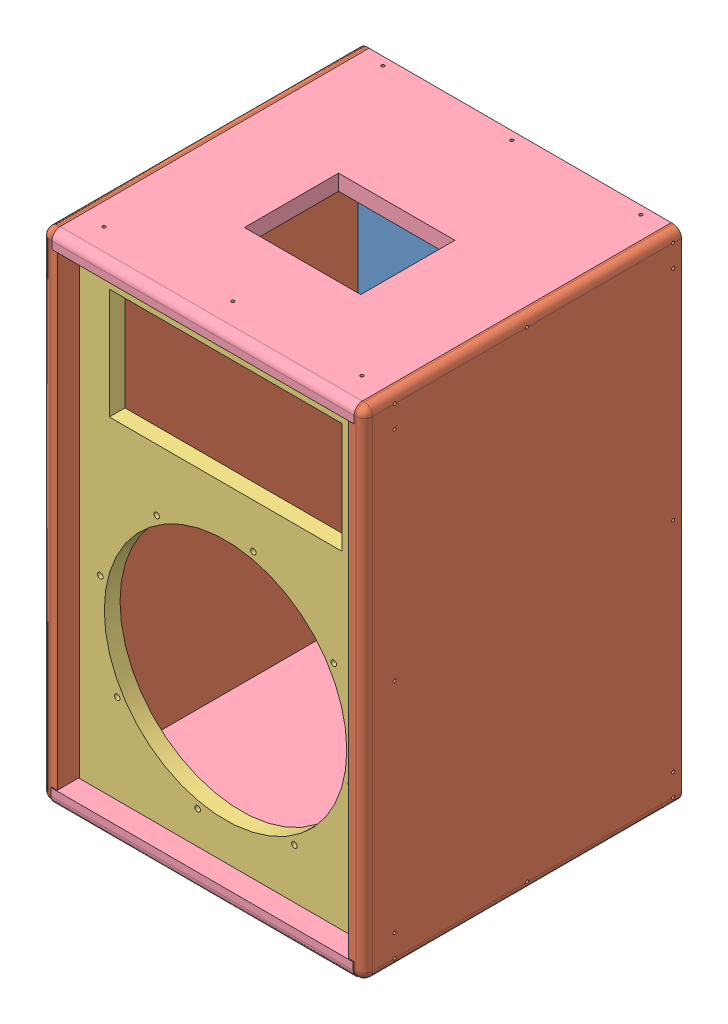
SolidWorks assembly SpeakerBox no electronics, configuration MetalGrill. Lengths in mm.
Overall size (370 570 364.9).
6 component instances, 5 part files, 12 mates.
Components (placement in the parent):
- back-1: back [Default] at (-203.5734 -231.6447 -35.6979) size (346.71 546.61 18)
- side-1: side [MetalGrill] at (-215.2134 -243.2947 339.8021) size (18 570 363.85)
- side-2: side [MetalGrill] at (154.7866 326.7053 339.8021) x (-1 0 0) z (0 0 1) size (18 570 363.85)
- Baffle-1: Baffle [Default] at (-202.5634 -231.6447 283.7021) size (345.7 544.6 18)
- top_btm-1: top_btm [MetalTop] at (143.1366 326.7053 -36.7479) x (-1 0 0) z (0 0 1) size (346.7 18 363.85)
- top_btm-2: top_btm [MetalBtm] at (-203.5634 -243.2947 -35.6979) size (346.7 18 363.85)
Mates (geometry in assembly coordinates):
- Coincident14: coincident anti-aligned: plane of side-1 through (-203.5634 320.3553 283.7021) normal (0 0 1); plane of Baffle-1 through (-202.5634 -231.6447 283.7021) normal (0 0 -1)
- Coincident16: coincident anti-aligned: plane of side-2 through (143.1366 326.7053 339.8021) normal (-1 0 0); plane of Baffle-1 through (143.1366 -231.6447 301.7021) normal (1 0 0)
- Coincident17: coincident anti-aligned: plane of side-1 through (-203.5634 -243.2947 339.8021) normal (1 0 0); plane of top_btm-1 through (-203.5634 308.7053 -36.7479) normal (-1 0 0)
- Coincident19: coincident aligned: plane of side-1 through (-197.2134 326.7053 339.8021) normal (0 1 0); plane of top_btm-1 through (143.1366 326.7053 -36.7479) normal (0 1 0)
- Coincident22: coincident aligned: plane of side-1 through (-197.2134 -243.2947 -36.7479) normal (0 0 -1); plane of top_btm-1 through (143.1366 308.7053 -36.7479) normal (0 0 -1)
- Coincident23: coincident aligned: plane of side-1 through (-197.2134 -243.2947 -36.7479) normal (0 0 -1); plane of side-2 through (136.7866 326.7053 -36.7479) normal (0 0 -1)
- Coincident24: coincident anti-aligned: plane of side-2 through (143.1366 326.7053 339.8021) normal (-1 0 0); plane of top_btm-1 through (143.1366 308.7053 -36.7479) normal (1 0 0)
- Coincident25: coincident anti-aligned: plane of side-2 through (143.1366 308.7053 339.8021) normal (0 1 0); plane of top_btm-1 through (143.1366 308.7053 -36.7479) normal (0 -1 0)
- Coincident28: coincident anti-aligned: plane of back-1 through (143.1366 -231.6447 -17.6979) normal (1 0 0); plane of side-2 through (143.1366 326.7053 339.8021) normal (-1 0 0)
- Coincident29: coincident anti-aligned: plane of Baffle-1 through (-202.5634 -231.6447 301.7021) normal (0 -1 0); plane of top_btm-2 through (-203.5634 -231.6447 -35.6979) normal (0 1 0)
- Coincident30: coincident aligned: plane of back-1 through (-203.5734 -231.6447 -35.6979) normal (0 0 -1); plane of top_btm-2 through (-203.5634 -225.2947 -35.6979) normal (0 0 -1)
- Coincident31: coincident anti-aligned: plane of side-2 through (143.1366 326.7053 339.8021) normal (-1 0 0); plane of top_btm-2 through (143.1366 -225.2947 -35.6979) normal (1 0 0)
